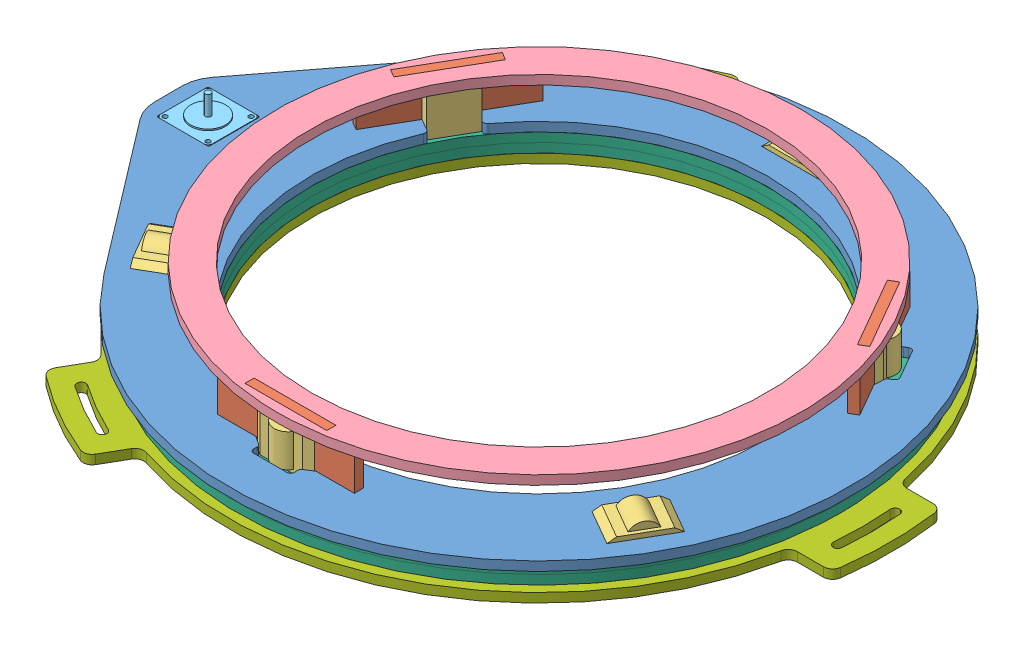
SolidWorks assembly Base Assembly - Plywood Parts, configuration Default. Lengths in mm.
Overall size (790.7 98.45 713.72).
16 component instances, 8 part files, 39 mates.
Components (placement in the parent):
- Base-1: Base [Default] at (-7.2575 72.4648 -45.052) size (745.7 50 680) (hidden)
- Base - Bottom Ring-1: Base - Bottom Ring [Default] at origin size (745.7 10 680)
- Base - Uprights-1: Base - Uprights [Default] at origin size (150 54.45 10)
- McMaster 2303T11-1: McMaster 2303T11 [Default] at (-7.2575 94.6898 229.8668) x (1 0 0) z (0 -1 0) size (62.32 36.6 44.45)
- Base - Top Ring-1: Base - Top Ring [Default] at (-7.2575 116.9148 -45.052) size (574.53 10 574.53)
- McMaster 2303T11-2: McMaster 2303T11 [Default] at (-7.2575 80.0836 -342.277) size (62.32 36.6 44.45)
- Base - Uprights-2: Base - Uprights [Default] at (28.13 0 -73.8631) x (-0.5 0 -0.866025) z (0.866025 0 -0.5) size (150 54.45 10)
- Base - Uprights-3: Base - Uprights [Default] at (-436.25 0 -301.1112) x (0.5 0 -0.866025) z (0.866025 0 0.5) size (150 54.45 10)
- McMaster 2303T11-3: McMaster 2303T11 [Default] at (-264.6619 80.0836 103.5605) x (0.5 0 0.866025) z (-0.866025 0 0.5) size (62.32 36.6 44.45)
- McMaster 2303T11-4: McMaster 2303T11 [Default] at (250.1469 80.0836 103.5605) x (0.5 0 -0.866025) z (0.866025 0 0.5) size (62.32 36.6 44.45)
- McMaster 2303T11-5: McMaster 2303T11 [Default] at (-245.3441 94.6898 -182.5114) x (-0.5 0 0.866025) z (0 -1 0) size (62.32 36.6 44.45)
- McMaster 2303T11-6: McMaster 2303T11 [Default] at (230.8291 94.6898 -182.5114) x (0.5 0 0.866025) z (0 1 0) size (62.32 36.6 44.45)
- Stepper (Sparkfun 125oz)-1: Stepper (Sparkfun 125oz) [Default] at (-397.9575 28.4648 -16.852) size (56.4 77.1 56.4)
- Base - Cable carrier ring-1: Base - Cable carrier ring [Default] at (0 72.4648 0) x (1 0 0) z (0 -1 0) size (660 660 10)
- Base - Cable carrier ring-2: Base - Cable carrier ring [Default] at (0 62.4648 0) x (1 0 0) z (0 -1 0) size (660 660 10)
- Base - Base Ring-1: Base - Base Ring [Default] at (-7.2575 42.4648 -45.052) size (725 10 713.72)
Mates (geometry in assembly coordinates):
- Coincident1: coincident anti-aligned: plane of Base - Uprights-1 through (-29.4825 82.4648 222.248) normal (1 0 0); plane of McMaster 2303T11-1 through (-29.4825 72.4648 232.248) normal (-1 0 0)
- Parallel1: parallel aligned: plane of Base - Bottom Ring-1 through (-825.2161 72.4648 -45.052) normal (0 -1 0); plane of McMaster 2303T11-1 through (-7.2575 72.4648 229.8668) normal (0 -1 0)
- Coincident3: coincident anti-aligned: plane of Base - Uprights-1 through (-82.2575 116.9148 232.248) normal (0 0 1); plane of McMaster 2303T11-1 through (-38.4173 72.4648 232.248) normal (0 0 -1)
- Coincident5: coincident aligned: plane of Base - Bottom Ring-1 through (-825.2161 72.4648 -45.052) normal (0 -1 0); plane of McMaster 2303T11-1 through (-7.2575 72.4648 229.8668) normal (0 -1 0)
- Concentric1: concentric aligned: circle of Base - Bottom Ring-1; circle of Base - Top Ring-1
- Coincident6: coincident anti-aligned: plane of Base - Uprights-1 through (37.522 116.9148 222.248) normal (0 1 0); plane of Base - Top Ring-1 through (-7.2575 116.9148 -45.052) normal (0 -1 0)
- Coincident7: coincident anti-aligned: plane of Base - Bottom Ring-1 through (-29.4825 72.4648 -45.052) normal (1 0 0); plane of McMaster 2303T11-2 through (-29.4825 82.4648 -320.052) normal (-1 0 0)
- Coincident8: coincident anti-aligned: plane of Base - Bottom Ring-1 through (-825.2161 72.4648 -364.502) normal (0 0 1); plane of McMaster 2303T11-2 through (-7.2575 80.0836 -364.502) normal (0 0 -1)
- Coincident9: coincident anti-aligned: plane of Base - Bottom Ring-1 through (-825.2161 82.4648 -45.052) normal (0 1 0); plane of McMaster 2303T11-2 through (-38.4173 82.4648 -320.052) normal (0 -1 0)
- Coincident10: coincident anti-aligned: plane of Base - Top Ring-1 through (201.8414 116.9148 -217.4821) normal (0.866025 0 -0.5); plane of Base - Uprights-2 through (261.7311 116.9148 -113.7501) normal (-0.866025 0 0.5)
- Coincident12: coincident anti-aligned: plane of Base - Top Ring-1 through (246.6208 116.9148 -139.9219) normal (-0.5 0 -0.866025); plane of Base - Uprights-2 through (246.6208 126.9148 -139.9219) normal (0.5 0 0.866025)
- Coincident13: coincident aligned: plane of Base - Top Ring-1 through (-7.2575 126.9148 -45.052) normal (0 1 0); plane of Base - Uprights-2 through (246.6208 126.9148 -139.9219) normal (0 1 0)
- Coincident14: coincident anti-aligned: plane of Base - Top Ring-1 through (-225.0166 116.9148 -222.4821) normal (0.866025 0 0.5); plane of Base - Uprights-3 through (-284.9063 116.9148 -118.7501) normal (-0.866025 0 -0.5)
- Coincident15: coincident aligned: plane of Base - Top Ring-1 through (-7.2575 126.9148 -45.052) normal (0 1 0); plane of Base - Uprights-3 through (-269.796 126.9148 -144.9219) normal (0 1 0)
- Coincident16: coincident anti-aligned: plane of Base - Top Ring-1 through (-216.3563 116.9148 -217.4821) normal (-0.5 0 0.866025); plane of Base - Uprights-3 through (-225.0166 126.9148 -222.4821) normal (0.5 0 -0.866025)
- Coincident17: coincident anti-aligned: plane of Base - Bottom Ring-1 through (-488.3989 72.4648 -239.5134) normal (0.866025 0 -0.5); plane of McMaster 2303T11-3 through (-283.9093 80.0836 114.673) normal (-0.866025 0 0.5)
- Coincident18: coincident anti-aligned: plane of Base - Bottom Ring-1 through (-609.6139 72.4648 328.3819) normal (-0.5 0 -0.866025); plane of McMaster 2303T11-3 through (-272.7968 82.4648 133.9204) normal (0.5 0 0.866025)
- Coincident19: coincident anti-aligned: plane of Base - Bottom Ring-1 through (-825.2161 82.4648 -45.052) normal (0 1 0); plane of McMaster 2303T11-3 through (-299.4892 82.4648 87.6878) normal (0 -1 0)
- Coincident20: coincident anti-aligned: plane of Base - Top Ring-1 through (-7.2575 116.9148 -45.052) normal (0 -1 0); plane of McMaster 2303T11-5 through (-245.3441 116.9148 -182.5114) normal (0 1 0)
- Coincident21: coincident anti-aligned: plane of Base - Uprights-3 through (-236.2938 82.4648 -202.9494) normal (-0.5 0 0.866025); plane of McMaster 2303T11-5 through (-236.2938 72.4648 -202.9494) normal (0.5 0 -0.866025)
- Coincident22: coincident anti-aligned: plane of Base - Uprights-3 through (-284.9063 116.9148 -118.7501) normal (-0.866025 0 -0.5); plane of McMaster 2303T11-5 through (-231.8264 72.4648 -210.6872) normal (0.866025 0 0.5)
- Coincident23: coincident anti-aligned: plane of Base - Bottom Ring-1 through (-609.6139 72.4648 -418.4859) normal (-0.5 0 0.866025); plane of McMaster 2303T11-4 through (280.5068 82.4648 95.4256) normal (0.5 0 -0.866025)
- Coincident24: coincident anti-aligned: plane of Base - Bottom Ring-1 through (26.4099 72.4648 446.6345) normal (0.866025 0 0.5); plane of McMaster 2303T11-4 through (230.8995 80.0836 92.448) normal (-0.866025 0 -0.5)
- Coincident25: coincident anti-aligned: plane of Base - Bottom Ring-1 through (-825.2161 82.4648 -45.052) normal (0 1 0); plane of McMaster 2303T11-4 through (253.8144 82.4648 141.6582) normal (0 -1 0)
- Coincident26: coincident anti-aligned: plane of Base - Uprights-2 through (235.3436 82.4648 -159.4546) normal (-0.5 0 -0.866025); plane of McMaster 2303T11-6 through (244.0039 116.9148 -164.4546) normal (0.5 0 0.866025)
- Coincident27: coincident anti-aligned: plane of Base - Top Ring-1 through (-7.2575 116.9148 -45.052) normal (0 -1 0); plane of McMaster 2303T11-6 through (230.8291 116.9148 -182.5114) normal (0 1 0)
- Coincident28: coincident anti-aligned: plane of Base - Uprights-2 through (270.3914 116.9148 -118.7501) normal (0.866025 0 -0.5); plane of McMaster 2303T11-6 through (217.3114 116.9148 -210.6872) normal (-0.866025 0 0.5)
- Coincident29: coincident anti-aligned: plane of Base - Bottom Ring-1 through (-397.9575 72.4648 -45.052) normal (1 0 0); plane of Stepper (Sparkfun 125oz)-1 through (-397.9575 82.4648 -68.622) normal (-1 0 0)
- Coincident30: coincident aligned: plane of Base - Bottom Ring-1 through (-825.2161 82.4648 -45.052) normal (0 1 0); plane of Stepper (Sparkfun 125oz)-1 through (-393.3275 82.4648 -68.622) normal (0 1 0)
- Coincident31: coincident anti-aligned: plane of Base - Bottom Ring-1 through (-825.2161 72.4648 -16.852) normal (0 0 -1); plane of Stepper (Sparkfun 125oz)-1 through (-393.3275 82.4648 -16.852) normal (0 0 1)
- InPlace1: in place: plane of ? through (-825.2161 72.4648 -45.052) normal (0 -1 0); plane of Base - Cable carrier ring-1 through (0 72.4648 0) normal (0 -1 0); moOrthogonalPlaneRef_w of ? through (-825.2161 72.4648 -45.052) normal (0 -1 0); plane of Base - Cable carrier ring-1 through (0 72.4648 0) normal (0 0 1); plane of ? through (-825.2161 72.4648 -45.052) normal (0 -1 0); line of Base - Cable carrier ring-1 through (-55 0 72.4648) axis (0 1 0); plane of ? through (-825.2161 72.4648 -45.052) normal (0 -1 0); unknown of Base - Cable carrier ring-1
- Coincident32: coincident aligned: plane of Base - Bottom Ring-1; plane of Base - Cable carrier ring-1
- Coincident33: coincident aligned: moOrthogonalPlaneRef_w of Base - Bottom Ring-1 through (0 72.4648 0) normal (0 0 1); plane of Base - Cable carrier ring-1 through (0 72.4648 0) normal (0 0 1)
- Coincident34: coincident anti-aligned: moOrthogonalPlaneRef_w of Base - Bottom Ring-1 through (0 72.4648 0) normal (-1 0 0); plane of Base - Cable carrier ring-1
- Coincident35: coincident anti-aligned: plane of Base - Cable carrier ring-1 through (-7.2575 62.4648 -45.052) normal (0 -1 0); plane of Base - Cable carrier ring-2 through (-7.2575 62.4648 -45.052) normal (0 1 0)
- Coincident36: coincident anti-aligned: plane of McMaster 2303T11-3 through (-283.9093 80.0836 114.673) normal (-0.866025 0 0.5); plane of Base - Cable carrier ring-2 through (-272.7968 52.4648 133.9204) normal (0.866025 0 -0.5)
- Coincident37: coincident anti-aligned: plane of McMaster 2303T11-2 through (14.9675 82.4648 -320.052) normal (1 0 0); plane of Base - Cable carrier ring-2 through (14.9675 52.4648 -364.502) normal (-1 0 0)
- Coincident38: coincident anti-aligned: plane of Base - Cable carrier ring-2 through (-7.2575 52.4648 -45.052) normal (0 -1 0); plane of Base - Base Ring-1 through (-7.2575 52.4648 -45.052) normal (0 1 0)
- Concentric2: concentric anti-aligned: cylinder of Base - Cable carrier ring-2 through (-7.2575 52.4648 -45.052) axis (0 1 0) radius 250; cylinder of Base - Base Ring-1 through (-7.2575 52.4648 -45.052) axis (0 -1 0) radius 250
